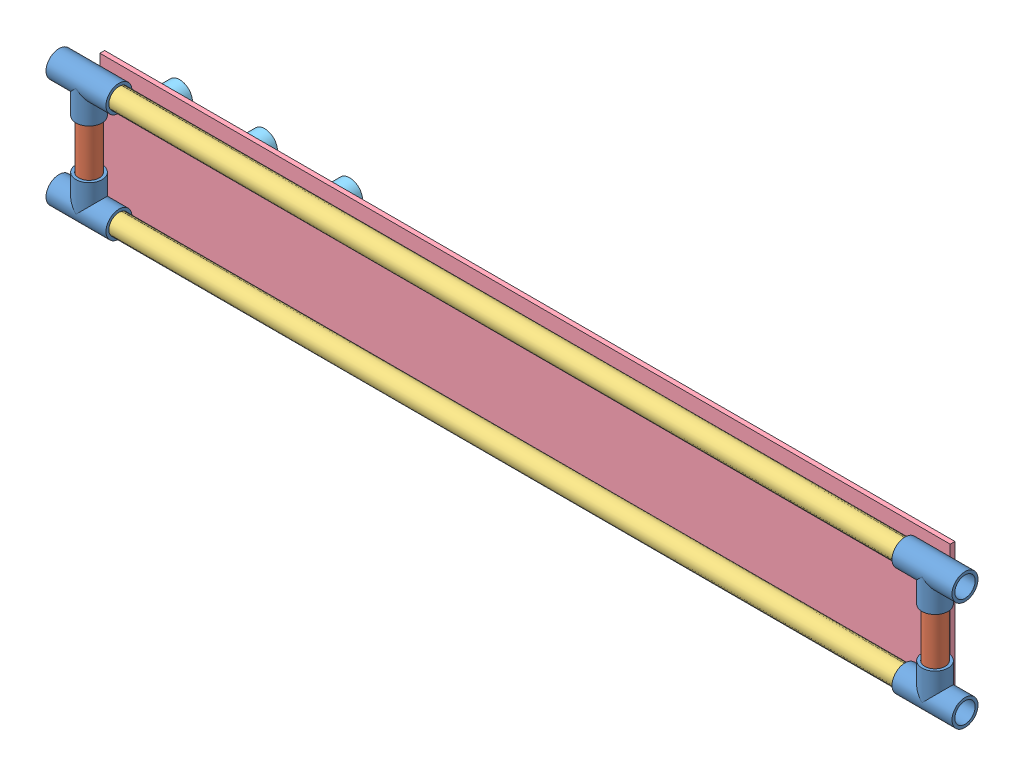
SolidWorks assembly ELEVATOR, configuration Default. Lengths in mm.
Overall size (958.9 150 62).
27 component instances, 6 part files, 25 mates.
Components (placement in the parent):
- 1-2 PVC TEE-1: 1-2 PVC TEE [4880K41] at (-33.6145 -12.3629 109.8998) size (63.5 45.53 27.56)
- 1-2 PVC TEE-2: 1-2 PVC TEE [4880K41] at (-929.0145 -12.3629 109.8998) size (63.5 45.53 27.56)
- 1-2 PVC TEE-3: 1-2 PVC TEE [4880K41] at (-33.6145 103.0371 109.8998) x (-1 0 0) z (0 0 1) size (63.5 45.53 27.56)
- 1-2 PVC TEE-4: 1-2 PVC TEE [4880K41] at (-929.0145 103.0371 109.8998) x (-1 0 0) z (0 0 1) size (63.5 45.53 27.56)
- 1-2 PVC PIPE 9CM-1: 1-2 PVC PIPE 9CM [48925K91] at (-33.6145 45.3371 109.8998) x (-1 0 0) z (0 -1 0) size (21.34 21.34 90)
- 1-2 PVC PIPE 9CM-2: 1-2 PVC PIPE 9CM [48925K91] at (-929.0145 45.3371 109.8998) x (-1 0 0) z (0 1 0) size (21.34 21.34 90)
- 1-2 PVC PIPE 87CM-1: 1-2 PVC PIPE 87CM [48925K91] at (-481.3145 103.0371 109.8998) x (0 0 1) z (1 0 0) size (21.34 21.34 870)
- 1-2 PVC PIPE 87CM-2: 1-2 PVC PIPE 87CM [48925K91] at (-481.3145 -12.3629 109.8998) x (0 0 1) z (-1 0 0) size (21.34 21.34 870)
- ELEVATOR B SHEET-1: ELEVATOR B SHEET [Default] at (-481.3145 45.3371 96.1203) x (1 0 0) z (0 1 0) size (900 5 150)
- 1-2 PVC CAP-1: 1-2 PVC CAP [4880K51] at (-881.3145 90.3371 76.401) x (0 0 1) z (-1 0 0) size (29.44 27.23 27.23)
- 1-2 PVC PIPE 1CM-1: 1-2 PVC PIPE 1CM [48925K91] at (-881.3145 90.3371 66.6817) size (21.34 21.34 10)
- 1-2 PVC CAP-2: 1-2 PVC CAP [4880K51] at (-881.3145 45.3371 76.401) x (0 0 1) z (-1 0 0) size (29.44 27.23 27.23)
- 1-2 PVC CAP-3: 1-2 PVC CAP [4880K51] at (-881.3145 0.3371 76.401) x (0 0 1) z (-1 0 0) size (29.44 27.23 27.23)
- 1-2 PVC PIPE 1CM-2: 1-2 PVC PIPE 1CM [48925K91] at (-881.3145 45.3371 66.6817) size (21.34 21.34 10)
- 1-2 PVC PIPE 1CM-3: 1-2 PVC PIPE 1CM [48925K91] at (-881.3145 0.3371 66.6817) size (21.34 21.34 10)
- 1-2 PVC PIPE 1CM-4: 1-2 PVC PIPE 1CM [48925K91] at (-791.3145 0.3371 66.6817) size (21.34 21.34 10)
- 1-2 PVC PIPE 1CM-5: 1-2 PVC PIPE 1CM [48925K91] at (-701.3145 0.3371 66.6817) size (21.34 21.34 10)
- 1-2 PVC CAP-4: 1-2 PVC CAP [4880K51] at (-791.3145 0.3371 76.401) x (0 0 1) z (-1 0 0) size (29.44 27.23 27.23)
- 1-2 PVC CAP-5: 1-2 PVC CAP [4880K51] at (-701.3145 0.3371 76.401) x (0 0 1) z (-1 0 0) size (29.44 27.23 27.23)
- 1-2 PVC PIPE 1CM-6: 1-2 PVC PIPE 1CM [48925K91] at (-791.3145 45.3371 66.6817) size (21.34 21.34 10)
- 1-2 PVC PIPE 1CM-7: 1-2 PVC PIPE 1CM [48925K91] at (-701.3145 45.3371 66.6817) size (21.34 21.34 10)
- 1-2 PVC CAP-6: 1-2 PVC CAP [4880K51] at (-791.3145 45.3371 76.401) x (0 0 1) z (-1 0 0) size (29.44 27.23 27.23)
- 1-2 PVC CAP-7: 1-2 PVC CAP [4880K51] at (-701.3145 45.3371 76.401) x (0 0 1) z (-1 0 0) size (29.44 27.23 27.23)
- 1-2 PVC CAP-8: 1-2 PVC CAP [4880K51] at (-791.3145 90.3371 76.401) x (0 0 1) z (-1 0 0) size (29.44 27.23 27.23)
- 1-2 PVC CAP-9: 1-2 PVC CAP [4880K51] at (-701.3145 90.3371 76.401) x (0 0 1) z (-1 0 0) size (29.44 27.23 27.23)
- 1-2 PVC PIPE 1CM-8: 1-2 PVC PIPE 1CM [48925K91] at (-791.3145 90.3371 66.6817) size (21.34 21.34 10)
- 1-2 PVC PIPE 1CM-9: 1-2 PVC PIPE 1CM [48925K91] at (-701.3145 90.3371 66.6817) size (21.34 21.34 10)
Mates (geometry in assembly coordinates):
- Coincident1: coincident anti-aligned: plane of 1-2 PVC TEE-3 through (-46.3145 103.0371 109.8998) normal (-1 0 0); plane of 1-2 PVC PIPE 87CM-1 through (-46.3145 103.0371 109.8998) normal (1 0 0)
- Concentric1: concentric anti-aligned: cone of 1-2 PVC TEE-3 through (-65.3645 103.0371 109.8998) axis (1 0 0); cylinder of 1-2 PVC PIPE 87CM-1 through (-46.3145 103.0371 109.8998) axis (-1 0 0) radius 10.668
- Coincident2: coincident anti-aligned: plane of 1-2 PVC TEE-4 through (-916.3145 103.0371 109.8998) normal (1 0 0); plane of 1-2 PVC PIPE 87CM-1 through (-916.3145 103.0371 109.8998) normal (-1 0 0)
- Concentric2: concentric anti-aligned: cylinder of 1-2 PVC TEE-4 through (-941.7145 103.0371 109.8998) axis (1 0 0) radius 13.7795; cylinder of 1-2 PVC PIPE 87CM-1 through (-46.3145 103.0371 109.8998) axis (-1 0 0) radius 10.668
- Coincident3: coincident anti-aligned: plane of 1-2 PVC TEE-3 through (-33.6145 90.3371 109.8998) normal (0 -1 0); plane of 1-2 PVC PIPE 9CM-1 through (-33.6145 90.3371 109.8998) normal (0 1 0)
- Concentric3: concentric aligned: cone of 1-2 PVC TEE-3 through (-33.6145 71.2871 109.8998) axis (0 1 0); cylinder of 1-2 PVC PIPE 9CM-1 through (-33.6145 0.3371 109.8998) axis (0 1 0) radius 10.668
- Coincident4: coincident anti-aligned: plane of 1-2 PVC TEE-4 through (-929.0145 90.3371 109.8998) normal (0 -1 0); plane of 1-2 PVC PIPE 9CM-2 through (-929.0145 90.3371 109.8998) normal (0 1 0)
- Concentric4: concentric anti-aligned: cone of 1-2 PVC TEE-4 through (-929.0145 71.2871 109.8998) axis (0 1 0); cylinder of 1-2 PVC PIPE 9CM-2 through (-929.0145 90.3371 109.8998) axis (0 -1 0) radius 10.668
- Coincident5: coincident anti-aligned: plane of 1-2 PVC TEE-1 through (-33.6145 0.3371 109.8998) normal (0 1 0); plane of 1-2 PVC PIPE 9CM-1 through (-33.6145 0.3371 109.8998) normal (0 -1 0)
- Concentric5: concentric anti-aligned: cone of 1-2 PVC TEE-1 through (-33.6145 19.3871 109.8998) axis (0 -1 0); cylinder of 1-2 PVC PIPE 9CM-1 through (-33.6145 0.3371 109.8998) axis (0 1 0) radius 10.668
- Coincident6: coincident anti-aligned: plane of 1-2 PVC TEE-2 through (-929.0145 0.3371 109.8998) normal (0 1 0); plane of 1-2 PVC PIPE 9CM-2 through (-929.0145 0.3371 109.8998) normal (0 -1 0)
- Concentric6: concentric aligned: cone of 1-2 PVC TEE-2 through (-929.0145 19.3871 109.8998) axis (0 -1 0); cylinder of 1-2 PVC PIPE 9CM-2 through (-929.0145 90.3371 109.8998) axis (0 -1 0) radius 10.668
- Coincident7: coincident anti-aligned: plane of 1-2 PVC TEE-2 through (-916.3145 -12.3629 109.8998) normal (1 0 0); plane of 1-2 PVC PIPE 87CM-2 through (-916.3145 -12.3629 109.8998) normal (-1 0 0)
- Concentric7: concentric anti-aligned: cone of 1-2 PVC TEE-2 through (-897.2645 -12.3629 109.8998) axis (-1 0 0); cylinder of 1-2 PVC PIPE 87CM-2 through (-916.3145 -12.3629 109.8998) axis (1 0 0) radius 10.668
- Concentric8: concentric anti-aligned: cylinder of 1-2 PVC TEE-1 through (-20.9145 -12.3629 109.8998) axis (-1 0 0) radius 13.7795; cylinder of 1-2 PVC PIPE 87CM-2 through (-916.3145 -12.3629 109.8998) axis (1 0 0) radius 10.668
- Parallel1: parallel anti-aligned: plane of ELEVATOR B SHEET-1 through (-481.3145 45.3371 96.1203) normal (0 0 -1); plane of assembly through (0 0 0) normal (0 0 1)
- Tangent1: tangent anti-aligned: cylinder of 1-2 PVC TEE-1 through (-20.9145 -12.3629 109.8998) axis (-1 0 0) radius 13.7795; plane of ELEVATOR B SHEET-1 through (-481.3145 45.3371 96.1203) normal (0 0 1)
- Coincident9: coincident aligned: plane of 1-2 PVC PIPE 87CM-1 through (-481.3145 103.0371 109.8998) normal (1 0 0); plane of ELEVATOR B SHEET-1
- Coincident10: coincident anti-aligned: plane of 1-2 PVC PIPE 9CM-1 through (-33.6145 45.3371 109.8998) normal (0 -1 0); plane of ELEVATOR B SHEET-1 through (-481.3145 45.3371 96.1203) normal (0 1 0)
- Coincident11: coincident aligned: plane of 1-2 PVC CAP-1 through (-881.3145 76.7227 61.6817) normal (0 0 -1); plane of 1-2 PVC PIPE 1CM-1 through (-881.3145 90.3371 61.6817) normal (0 0 -1)
- Concentric9: concentric anti-aligned: cone of 1-2 PVC CAP-1 through (-881.3145 90.3371 79.8173) axis (0 0 1); cylinder of 1-2 PVC PIPE 1CM-1 through (-881.3145 90.3371 71.6817) axis (0 0 -1) radius 7.8994
- Parallel2: parallel aligned: plane of ELEVATOR B SHEET-1 through (-481.3145 45.3371 91.1203) normal (0 0 -1); plane of 1-2 PVC CAP-1 through (-881.3145 76.7227 61.6817) normal (0 0 -1)
- Tangent2: tangent: plane of ELEVATOR B SHEET-1 through (-481.3145 45.3371 91.1203) normal (0 0 -1); face of 1-2 PVC CAP-1
- Distance1: distance = 50 mm aligned: plane of 1-2 PVC CAP-1 through (-881.3145 90.3371 76.401) normal (-1 0 0); plane of ELEVATOR B SHEET-1 through (-931.3145 120.3371 91.1203) normal (-1 0 0)
- Distance2: distance = 30 mm aligned: plane of 1-2 PVC CAP-1; plane of ELEVATOR B SHEET-1 through (-931.3145 120.3371 91.1203) normal (0 1 0)
